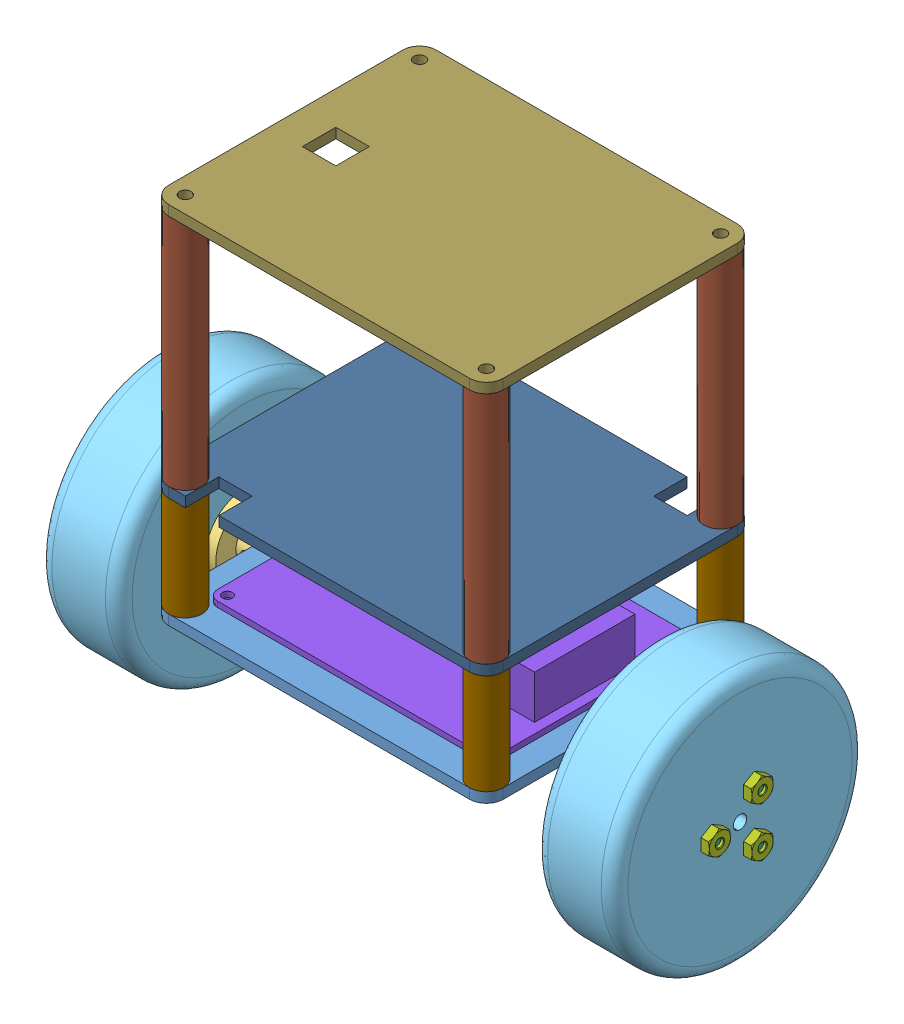
SolidWorks assembly Assem1, configuration Default. Lengths in mm.
Overall size (177.86 165.23 103.14).
34 component instances, 12 part files, 35 mates.
Components (placement in the parent):
- 05_plate_0-1: 05_plate_0 [Default] at (56.2824 96.5369 150.2079) size (100 3 80)
- motor_assembly-1: motor_assembly [Default] at (76.944 129.3735 158.3262) x (0 0 -1) z (0 -1 0) size (102.45 66.46 102.45)
  - 01_micro_metal_gearmotor-1: 01_micro_metal_gearmotor [По умолчанию] at (7.6392 6.8545 37.8366) size (12.1 35.27 10.12)
  - 02_motor_hub-1: 02_motor_hub [Default] at (7.6392 33.6245 37.8366) x (0 0 -1) z (1 0 0) size (23 8 23)
  - 03_motor_mount-1: 03_motor_mount [Default] at (-5.1608 -3.6518 104.3827) x (0 0.08713 -0.996197) z (1 0 0) size (12.96 18.24 26.57)
  - 04_wheel-1: 04_wheel [Default] at (7.6392 41.6245 37.8366) x (0.866025 0 -0.5) z (0 1 0) size (75 75 24)
  - pan cross head_ai-1: pan cross head_ai [CR-PHMS 0.112-40x1.125x1.125-N] at (-0.8608 36.5925 37.8366) x (0 1 0) z (0 0 1) size (30.57 5.56 5.56)
  - pan cross head_ai-2: pan cross head_ai [CR-PHMS 0.112-40x1.125x1.125-N] at (11.8892 36.5925 30.4754) x (0 1 0) z (-0.866025 0 -0.5) size (30.57 5.56 5.56)
  - pan cross head_ai-3: pan cross head_ai [CR-PHMS 0.112-40x1.125x1.125-N] at (11.8892 36.5925 45.1978) x (0 1 0) z (0.866025 0 -0.5) size (30.57 5.56 5.56)
  - machine screw nut hex_ai-1: machine screw nut hex_ai [MSHXNUT 0.112-48-S-N] at (-0.8608 68.1137 37.8366) x (1 0 0) z (0 1 0) size (6.35 7.33 2.49)
  - machine screw nut hex_ai-2: machine screw nut hex_ai [MSHXNUT 0.112-48-S-N] at (11.8892 68.1137 45.1978) x (-0.5 0 -0.866025) z (0 1 0) size (6.35 7.33 2.49)
  - machine screw nut hex_ai-3: machine screw nut hex_ai [MSHXNUT 0.112-48-S-N] at (11.8892 68.1137 30.4754) x (-0.5 0 0.866025) z (0 1 0) size (6.35 7.33 2.49)
- motor_assembly-2: motor_assembly [Default] at (35.3158 129.3735 142.3644) x (0 0 1) z (0 -1 0) size (102.45 66.46 102.45)
  - 01_micro_metal_gearmotor-1: 01_micro_metal_gearmotor [По умолчанию] at (7.6392 6.8545 37.8366) size (12.1 35.27 10.12)
  - 02_motor_hub-1: 02_motor_hub [Default] at (7.6392 33.6245 37.8366) x (0 0 -1) z (1 0 0) size (23 8 23)
  - 03_motor_mount-1: 03_motor_mount [Default] at (-5.1608 -3.6518 104.3827) x (0 0.08713 -0.996197) z (1 0 0) size (12.96 18.24 26.57)
  - 04_wheel-1: 04_wheel [Default] at (7.6392 41.6245 37.8366) x (0.866025 0 -0.5) z (0 1 0) size (75 75 24)
  - pan cross head_ai-1: pan cross head_ai [CR-PHMS 0.112-40x1.125x1.125-N] at (-0.8608 36.5925 37.8366) x (0 1 0) z (0 0 1) size (30.57 5.56 5.56)
  - pan cross head_ai-2: pan cross head_ai [CR-PHMS 0.112-40x1.125x1.125-N] at (11.8892 36.5925 30.4754) x (0 1 0) z (-0.866025 0 -0.5) size (30.57 5.56 5.56)
  - pan cross head_ai-3: pan cross head_ai [CR-PHMS 0.112-40x1.125x1.125-N] at (11.8892 36.5925 45.1978) x (0 1 0) z (0.866025 0 -0.5) size (30.57 5.56 5.56)
  - machine screw nut hex_ai-1: machine screw nut hex_ai [MSHXNUT 0.112-48-S-N] at (-0.8608 68.1137 37.8366) x (1 0 0) z (0 1 0) size (6.35 7.33 2.49)
  - machine screw nut hex_ai-2: machine screw nut hex_ai [MSHXNUT 0.112-48-S-N] at (11.8892 68.1137 45.1978) x (-0.5 0 -0.866025) z (0 1 0) size (6.35 7.33 2.49)
  - machine screw nut hex_ai-3: machine screw nut hex_ai [MSHXNUT 0.112-48-S-N] at (11.8892 68.1137 30.4754) x (-0.5 0 0.866025) z (0 1 0) size (6.35 7.33 2.49)
- 06_mdd10a-1: 06_mdd10a [Default] at (56.2824 99.5369 150.2079) size (84.8 14.65 62)
- 07_rod_3mm-1: 07_rod_3mm [Default] at (11.2824 99.5369 185.2079) x (0.868762 0 0.49523) z (-0.49523 0 0.868762) size (10 30 10)
- 07_rod_3mm-2: 07_rod_3mm [Default] at (101.2824 99.5369 115.2079) size (10 30 10)
- 07_rod_3mm-3: 07_rod_3mm [Default] at (101.2824 129.5369 185.2079) x (-0.727661 0 -0.685936) z (-0.685936 0 0.727661) size (10 30 10)
- 07_rod_3mm-4: 07_rod_3mm [Default] at (11.2824 129.5369 115.2079) x (-0.781501 0 -0.623904) z (-0.623904 0 0.781501) size (10 30 10)
- 05_plate_1-1: 05_plate_1 [Default] at (56.2824 129.5369 150.2079) size (100 3 80)
- 07_rod_7mm-1: 07_rod_7mm [Default] at (101.2824 132.5369 185.2079) x (0.782948 0 -0.622087) z (0.622087 0 0.782948) size (10 70 10)
- 07_rod_7mm-2: 07_rod_7mm [Default] at (11.2824 132.5369 115.2079) x (0.827033 0 0.562154) z (-0.562154 0 0.827033) size (10 70 10)
- 07_rod_7mm-3: 07_rod_7mm [Default] at (11.2824 132.5369 185.2079) x (0.963961 0 0.266044) z (-0.266044 0 0.963961) size (10 70 10)
- 07_rod_7mm-4: 07_rod_7mm [Default] at (101.2824 132.5369 115.2079) x (0.975849 0 -0.218448) z (0.218448 0 0.975849) size (10 70 10)
- 05_plate_2-1: 05_plate_2 [Default] at (56.2824 202.5369 150.2079) size (100 3 80)
Mates (geometry in assembly coordinates):
- Parallel5: parallel anti-aligned: plane of 05_plate_0-1 through (6.2824 99.5369 115.2079) normal (-1 0 0); plane of motor_assembly-1/01_micro_metal_gearmotor-1 through (106.2985 91.5369 150.687) normal (1 0 0)
- Coincident5: coincident anti-aligned: plane of 05_plate_0-1 through (101.2824 96.5369 115.2079) normal (0 -1 0); plane of motor_assembly-1/01_micro_metal_gearmotor-1 through (97.2985 96.5369 154.0036) normal (0 1 0)
- Parallel6: parallel aligned: plane of 05_plate_0-1 through (6.2824 99.5369 115.2079) normal (-1 0 0); plane of motor_assembly-2/01_micro_metal_gearmotor-1 through (5.9613 91.5369 150.0036) normal (-1 0 0)
- Coincident7: coincident anti-aligned: plane of 05_plate_0-1 through (101.2824 96.5369 115.2079) normal (0 -1 0); plane of motor_assembly-2/01_micro_metal_gearmotor-1 through (14.9613 96.5369 146.687) normal (0 1 0)
- Lock1: lock: unknown of 05_plate_0-1; unknown of motor_assembly-2/03_motor_mount-1
- Lock2: lock: unknown of 05_plate_0-1; unknown of motor_assembly-1/03_motor_mount-1
- Coincident10: coincident aligned: plane of 05_plate_0-1 through (101.2824 99.5369 115.2079) normal (0 1 0); circle of 07_rod_3mm-1
- Coincident11: coincident anti-aligned: plane of 05_plate_0-1 through (101.2824 99.5369 115.2079) normal (0 1 0); plane of 07_rod_3mm-2 through (101.2824 99.5369 115.2079) normal (0 -1 0)
- Coincident12: coincident anti-aligned: plane of 05_plate_0-1 through (101.2824 99.5369 115.2079) normal (0 1 0); circle of 07_rod_3mm-3
- Coincident13: coincident anti-aligned: plane of 05_plate_0-1 through (101.2824 99.5369 115.2079) normal (0 1 0); circle of 07_rod_3mm-4
- Concentric4: concentric anti-aligned: circle of 05_plate_0-1; circle of 07_rod_3mm-1
- Concentric5: concentric anti-aligned: circle of 05_plate_0-1; cylinder of 07_rod_3mm-3 through (101.2824 129.5369 185.2079) axis (0 -1 0) radius 2
- Concentric6: concentric anti-aligned: circle of 05_plate_0-1; circle of 07_rod_3mm-2
- Concentric7: concentric aligned: circle of 05_plate_0-1; circle of 07_rod_3mm-4
- Concentric9: concentric aligned: circle of 05_plate_0-1; circle of 06_mdd10a-1
- Concentric8: concentric aligned: circle of 05_plate_0-1; circle of 06_mdd10a-1
- Coincident16: coincident anti-aligned: plane of 05_plate_0-1 through (101.2824 99.5369 115.2079) normal (0 1 0); plane of 06_mdd10a-1 through (56.2824 99.5369 150.2079) normal (0 -1 0)
- Concentric10: concentric aligned: circle of 07_rod_3mm-3; circle of 05_plate_1-1
- Concentric11: concentric aligned: cylinder of 07_rod_3mm-1 through (11.2824 99.5369 185.2079) axis (0 1 0) radius 2; circle of 05_plate_1-1
- Concentric12: concentric aligned: circle of 07_rod_3mm-4; circle of 05_plate_1-1
- Concentric13: concentric anti-aligned: circle of 07_rod_3mm-2; circle of 05_plate_1-1
- Coincident17: coincident anti-aligned: circle of 07_rod_3mm-1; plane of 05_plate_1-1 through (101.2824 129.5369 115.2079) normal (0 -1 0)
- Concentric14: concentric anti-aligned: circle of 05_plate_1-1; circle of 07_rod_7mm-1
- Coincident18: coincident anti-aligned: plane of 05_plate_1-1 through (101.2824 132.5369 115.2079) normal (0 1 0); plane of 07_rod_7mm-1 through (101.2824 132.5369 185.2079) normal (0 -1 0)
- Concentric15: concentric aligned: circle of 05_plate_1-1; cylinder of 07_rod_7mm-3 through (11.2824 132.5369 185.2079) axis (0 1 0) radius 2
- Coincident19: coincident: plane of 05_plate_1-1 through (101.2824 132.5369 115.2079) normal (0 1 0); line of 07_rod_7mm-3 through (12.0939 132.5369 188.2778) axis (0.709484 0 -0.704722)
- Concentric16: concentric anti-aligned: circle of 05_plate_1-1; circle of 07_rod_7mm-2
- Coincident20: coincident anti-aligned: plane of 05_plate_1-1 through (101.2824 132.5369 115.2079) normal (0 1 0); plane of 07_rod_7mm-2 through (11.2824 132.5369 115.2079) normal (0 -1 0)
- Concentric17: concentric anti-aligned: circle of 05_plate_1-1; circle of 07_rod_7mm-4
- Coincident21: coincident anti-aligned: plane of 05_plate_1-1 through (101.2824 132.5369 115.2079) normal (0 1 0); plane of 07_rod_7mm-4 through (101.2824 132.5369 115.2079) normal (0 -1 0)
- Concentric18: concentric anti-aligned: circle of 07_rod_7mm-3; circle of 05_plate_2-1
- Concentric19: concentric anti-aligned: circle of 07_rod_7mm-1; circle of 05_plate_2-1
- Concentric20: concentric aligned: cylinder of 07_rod_7mm-4 through (101.2824 132.5369 115.2079) axis (0 1 0) radius 2; circle of 05_plate_2-1
- Concentric21: concentric anti-aligned: circle of 07_rod_7mm-2; circle of 05_plate_2-1
- Coincident22: coincident anti-aligned: circle of 07_rod_7mm-2; plane of 05_plate_2-1 through (101.2824 202.5369 115.2079) normal (0 -1 0)
